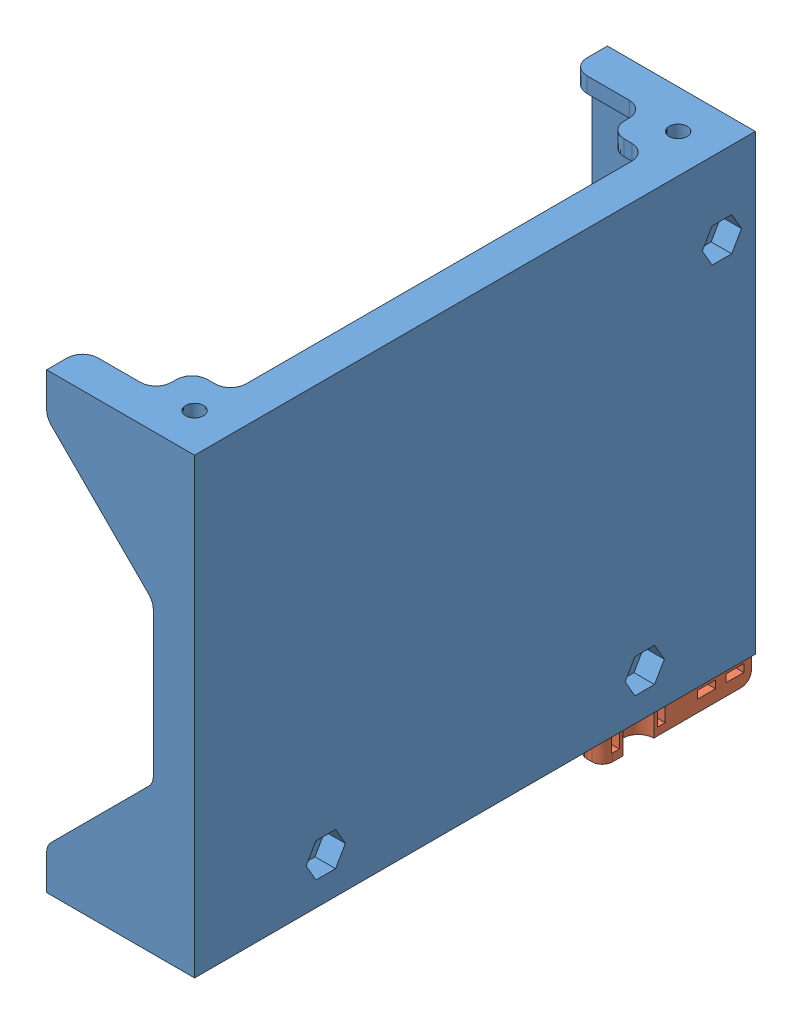
SolidWorks assembly Assem1, configuration Default. Lengths in mm.
Overall size (28.75 106 122).
2 component instances, 2 part files, 3 mates.
Components (placement in the parent):
- ElectronicsHolder-1: ElectronicsHolder [Default] at (49.7706 109.8963 64.1448) size (28.75 88 109)
- SideHolder-1: SideHolder [Default] at (54.7706 23.3963 21.6448) x (-1 0 0) z (0 -1 0) size (15 35 18)
Mates (geometry in assembly coordinates):
- Coincident1: coincident anti-aligned: plane of ElectronicsHolder-1 through (49.7706 23.3963 64.1448) normal (0 -1 0); plane of SideHolder-1 through (54.7706 23.3963 21.6448) normal (0 1 0)
- Concentric1: concentric anti-aligned: cylinder of ElectronicsHolder-1 through (53.7706 33.3963 26.6448) axis (0 -1 0) radius 1.75; cylinder of SideHolder-1 through (53.7706 19.3963 26.6448) axis (0 1 0) radius 1.75
- Concentric2: concentric anti-aligned: cylinder of ElectronicsHolder-1 through (53.7706 33.3963 16.6448) axis (0 -1 0) radius 1.75; cylinder of SideHolder-1 through (53.7706 19.3963 16.6448) axis (0 1 0) radius 1.75
